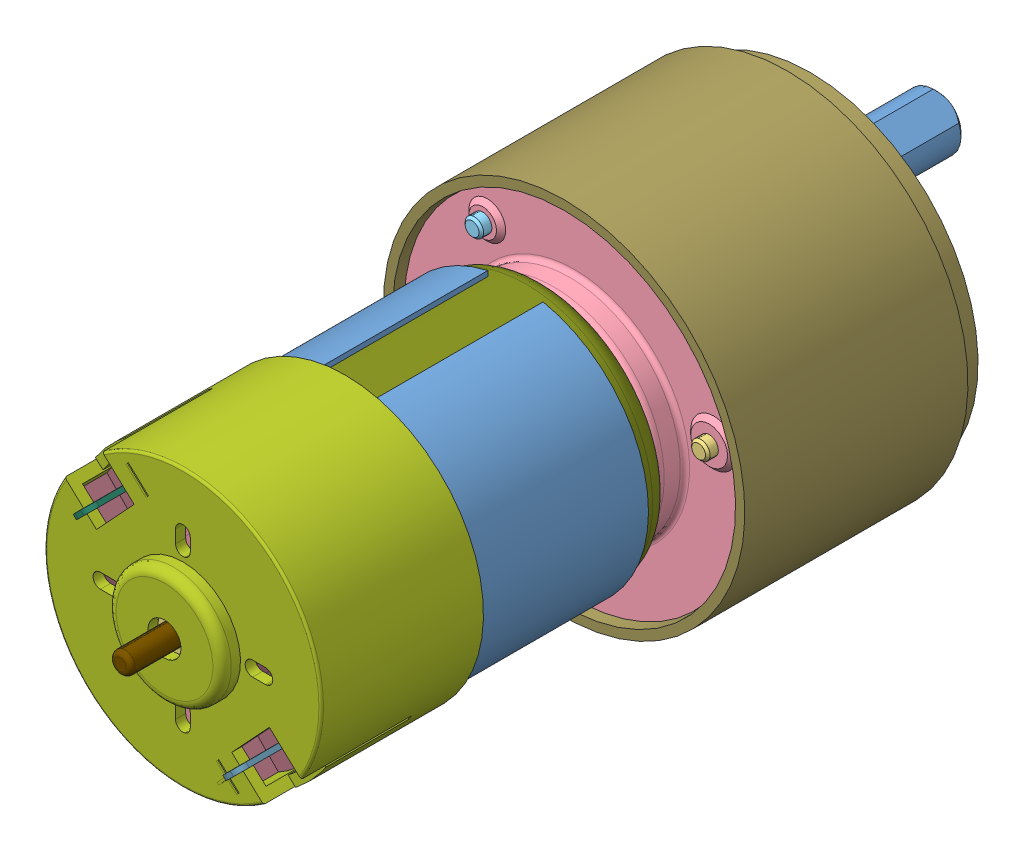
SolidWorks assembly Mclennan_1308-3stage, configuration Default. Lengths in mm.
Overall size (39.2 39.2 95.66).
37 component instances, 25 part files, 0 mates.
Components (placement in the parent):
- Mclennan_1308-3stage.stp-1: Mclennan_1308-3stage.stp [Default] at origin size (39.2 39.2 95.66)
  - Gearbox Assy -250.stp-1: Gearbox Assy -250.stp [Default] at (-105.6205 -45.8374 375.8238) x (0 -1 0) z (0 0 1) size (39.2 39.2 48.06)
    - OP Shaft.stp-1: OP Shaft.stp [Default] at (12.9434 -8.3803 -3.7831) size (19.48 19.5 45.41)
      - Shaft.stp-1: Shaft.stp [Default] at (-8.2426 6.4494 -61.4452) size (6 6 45.41)
      - Spur Gear.stp-1: Spur Gear.stp [Default] at (-8.2426 6.4494 -34.2456) size (19.48 19.5 3)
    - Gearbox screw assy.stp-1: Gearbox screw assy.stp [Default] at (0 0 19.3148) size (3.85 3.85 26.2)
      - Screw _ Pan - M2.0 x 25.0.stp-1: Screw _ Pan - M2.0 x 25.0.stp [Default] at (0.9038 20.1559 -61.4931) x (1 0 0) z (0 0 -1) size (3.85 3.85 26.2)
      - Washer _ Plain - M2.0 x 0.75.stp-1: Washer _ Plain - M2.0 x 0.75.stp [Default] at (0.9038 20.1559 -61.4931) size (3.8 3.8 0.75)
    - Gearbox screw assy-1.stp-1: Gearbox screw assy-1.stp [Default] at (-8.628 -24.5638 19.3148) size (3.85 3.85 26.2)
      - Screw _ Pan - M2.0 x 25.0-0.stp-1: Screw _ Pan - M2.0 x 25.0-0.stp [Default] at (0.9038 20.1559 -61.4931) x (1 0 0) z (0 0 -1) size (3.85 3.85 26.2)
      - Washer _ Plain - M2.0 x 0.75-1.stp-1: Washer _ Plain - M2.0 x 0.75-1.stp [Default] at (0.9038 20.1559 -61.4931) size (3.8 3.8 0.75)
    - Gearbox screw assy-2.stp-1: Gearbox screw assy-2.stp [Default] at (16.222 -24.5638 19.3148) size (3.85 3.85 26.2)
      - Screw _ Pan - M2.0 x 25.0-2.stp-1: Screw _ Pan - M2.0 x 25.0-2.stp [Default] at (0.9038 20.1559 -61.4931) x (1 0 0) z (0 0 -1) size (3.85 3.85 26.2)
      - Washer _ Plain - M2.0 x 0.75-3.stp-1: Washer _ Plain - M2.0 x 0.75-3.stp [Default] at (0.9038 20.1559 -61.4931) size (3.8 3.8 0.75)
    - Gearbox plates.stp-1: Gearbox plates.stp [Default] at (4.7008 5.0251 -40.3283) size (36.95 36.95 20.4)
    - Plate pillar.stp-1: Plate pillar.stp [Default] at (0.9038 20.1559 -36.8283) size (3 3 20.9)
    - Plate pillar.stp-2: Plate pillar.stp [Default] at (-7.7242 -4.4078 -36.8283) size (3 3 20.9)
    - Plate pillar.stp-3: Plate pillar.stp [Default] at (17.1258 -4.4078 -36.8283) size (3 3 20.9)
    - OP boss.stp-1: OP boss.stp [Default] at (4.7008 -1.9308 -45.9229) size (11.9 11.9 11.4)
    - Gearbox body.stp-1: Gearbox body.stp [Default] at (4.7008 5.0251 -41.9283) size (39.2 39.2 26.7)
  - Motor assy.stp-1: Motor assy.stp [Default] at (-76.4794 -50.8527 310.5067) x (0 -1 0) z (0 0 1) size (38.89 38.89 56.6)
    - Motor.stp-1: Motor.stp [Default] at origin size (38.89 38.89 56.6)
      - Rear assy.stp-1: Rear assy.stp [Default] at (23.8016 -24.4305 0) x (0 -1 0) z (0 0 1) size (27.4 27.4 9.2)
        - Motor rear moulding.stp-1: Motor rear moulding.stp [Default] at (-0.3145 -24.1161 77.8388) size (27.4 27.4 7)
        - Positive terminal.stp-1: Positive terminal.stp [Default] at (-33.5724 -28.922 74.0682) size (2.34 2.32 6.7)
        - Negative terminal.stp-1: Negative terminal.stp [Default] at origin size (2.34 2.32 6.7)
      - Motor shell.stp-1: Motor shell.stp [Default] at (-0.3145 -24.1161 34.2388) x (0.707107 -0.707107 0) z (0 0 1) size (27.5 27.5 37.5)
      - Front bearing.stp-1: Front bearing.stp [Default] at (-0.3145 -24.1161 47.7388) size (8 8 2)
      - Shaft-4.stp-1: Shaft-4.stp [Default] at (-0.3145 -24.1161 39.7388) size (2.3 2.3 56)
      - Body sleeve.stp-1: Body sleeve.stp [Default] at (-0.3145 -24.1161 52.7388) size (28.31 28.6 22)
      - Single Helical Gear.stp-1: Single Helical Gear.stp [Default] at (-0.3145 -24.1161 39.1388) size (5.49 5.49 4.5)
      - Rear bearing.stp-1: Rear bearing.stp [Default] at (-0.3145 -24.1161 87.8388) size (4 4 2)
    - Motor mount.stp-1: Motor mount.stp [Default] at (-0.3145 -24.1161 45.3888) size (36.9 36.9 4.35)
    - Screw _ Pan - M2.5 x 4.0.stp-1: Screw _ Pan - M2.5 x 4.0.stp [Default] at (-0.3145 -32.1161 47.7888) x (1 0 0) z (0 0 -1) size (4.65 4.65 5.4)
    - Screw _ Pan - M2.5 x 4.0.stp-2: Screw _ Pan - M2.5 x 4.0.stp [Default] at (-0.3145 -16.1161 47.7888) x (1 0 0) z (0 0 -1) size (4.65 4.65 5.4)
    - Motor retaining ring.stp-1: Motor retaining ring.stp [Default] at (-0.3145 -24.1161 45.9388) size (21.5 21.5 2.6)
    - Motor cover.stp-1: Motor cover.stp [Default] at (-0.3145 -24.1161 71.3388) size (30 30 19.6)
